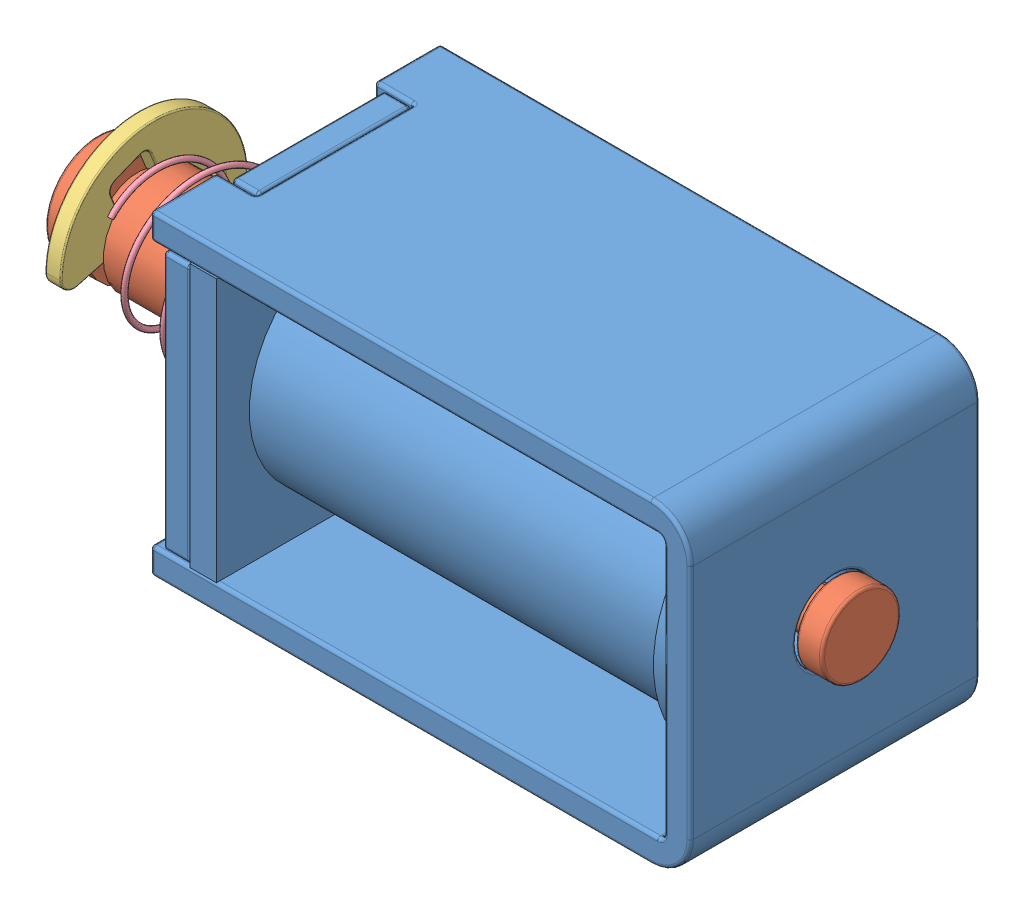
SolidWorks assembly Solenoid, configuration Default. Lengths in mm.
Overall size (29 12 11).
5 component instances, 4 part files, 3 mates.
Components (placement in the parent):
- Shell-1: Shell [Default] at origin size (20.5 12 11)
- Shaft Assem-1: Shaft Assem [Default] at (2.5 -6 5.5) x (0 0.575247 0.81798) z (1 0 0) size (7.1 6.76 29)
  - Shaft-1: Shaft [Default] at origin size (4 4 29)
  - Circlip-1: Circlip [Default] at (0 0 -8.45) size (7.1 5.79 0.6)
  - Spring-1: Spring [Default] at (0 0 -2.3) x (-1 0 0) z (0 0 -1) size (6.3 6.5 5.85)
Mates (geometry in assembly coordinates):
- Coincident1: coordinate: point of Shell-1; point of assembly
- Concentric1: concentric anti-aligned: cylinder of Shell-1 through (0 -6 5.5) axis (1 0 0) radius 1.5; cylinder of Shaft Assem-1/Shaft-1 through (20.5 -6 5.5) axis (-1 0 0) radius 0.775
- Coincident2: coincident anti-aligned: plane of Shell-1 through (20.5 0 11) normal (1 0 0); plane of Shaft Assem-1/Shaft-1 through (20.5 -6 5.5) normal (-1 0 0)
